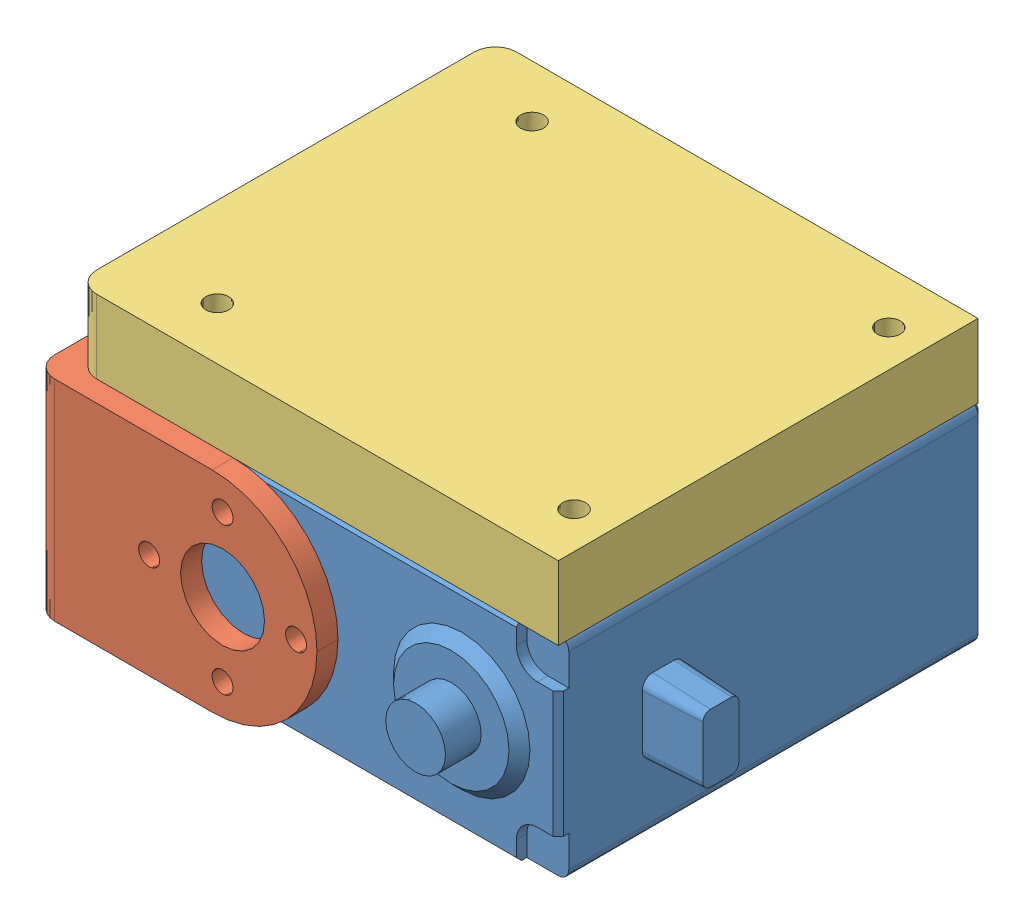
SolidWorks assembly moteur-complet, configuration Défaut. Lengths in mm.
Overall size (56.5 27 48.8).
11 component instances, 5 part files, 26 mates.
Components (placement in the parent):
- moteur-1: moteur [Défaut] at (-9.5825 -1.0731 48.8) size (45.5 20 48.8)
- moteur-support-fixe-1: moteur-support-fixe [Défaut] at (-5.7196 9.1116 15.94) x (1 0 0) z (0 -1 0) size (27.58 44 20)
- moteur_semelle-1: moteur_semelle [Défaut] at (-31.3007 -10.8884 28.8) x (-1 0 0) z (0 0 1) size (46 27 40)
- ecrou-h-1: ecrou-h [6012 HU M3] at (-26.9007 -5.8884 23.8) x (0 0.5 -0.866025) z (0 -0.866025 -0.5) size (5.5 2.4 6.35)
- ecrou-h-2: ecrou-h [6012 HU M3] at (-26.9007 -5.8884 33.8) x (0 -0.5 -0.866025) z (0 -0.866025 0.5) size (5.5 2.4 6.35)
- ecrou-h-3: ecrou-h [6012 HU M3] at (-26.9007 4.1116 33.8) x (0 -0.5 -0.866025) z (0 -0.866025 0.5) size (5.5 2.4 6.35)
- ecrou-h-4: ecrou-h [6012 HU M3] at (-26.9007 4.1116 23.8) x (0 -1 0) z (0 0 1) size (5.5 2.4 6.35)
- vis-chc-1: vis-chc [Vis CHC M3x6] at (-33.3007 -5.8884 33.8) x (0 -0.454411 0.890792) z (0 -0.890792 -0.454411) size (5.5 9 5.5)
- vis-chc-2: vis-chc [Vis CHC M3x6] at (-33.3007 4.1116 33.8) x (0 -0.381849 0.924225) z (0 -0.924225 -0.381849) size (5.5 9 5.5)
- vis-chc-3: vis-chc [Vis CHC M3x6] at (-33.3007 4.1116 23.8) x (0 -0.381849 0.924225) z (0 -0.924225 -0.381849) size (5.5 9 5.5)
- vis-chc-4: vis-chc [Vis CHC M3x6] at (-33.3007 -5.8884 23.8) x (0 -0.381849 0.924225) z (0 -0.924225 -0.381849) size (5.5 9 5.5)
Mates (geometry in assembly coordinates):
- Coaxiale12: concentric aligned: cylinder of moteur-1 through (-22.3007 -0.8884 43.8) axis (0 0 1) radius 0.79; cylinder of moteur-support-fixe-1 through (-22.3007 -0.8884 6.799) axis (0 0 1) radius 1
- Coaxiale13: concentric aligned: cylinder of moteur-1 through (-15.3007 -7.8884 43.8) axis (0 0 1) radius 0.79; cylinder of moteur-support-fixe-1 through (-15.3007 -7.8884 6.799) axis (0 0 1) radius 1
- Coïncidente2: coincident anti-aligned: plane of moteur-1 through (-9.5825 -1.0731 48.8) normal (0 0 1); plane of moteur-support-fixe-1 through (-29.3007 -10.8884 48.8) normal (0 0 -1)
- Coïncidente3: coincident anti-aligned: plane of moteur-support-fixe-1 through (-31.3007 -10.8884 10.8) normal (1 0 0); plane of moteur_semelle-1 through (-31.3007 16.1116 8.8) normal (-1 0 0)
- Coïncidente5: coincident anti-aligned: plane of moteur-1 through (-25.3007 9.1116 8.3) normal (0 1 0); plane of moteur_semelle-1 through (14.6993 9.1116 48.8) normal (0 -1 0)
- Coaxiale15: concentric anti-aligned: cylinder of moteur_semelle-1 through (14.7003 -5.8884 23.8) axis (-1 0 0) radius 1.6; cylinder of ecrou-h-1 through (-29.3007 -5.8884 23.8) axis (1 0 0) radius 1.2295
- Parallèle2: parallel anti-aligned: plane of moteur_semelle-1 through (-29.3007 -8.9195 25.55) normal (0 1 0); plane of ecrou-h-1 through (-29.3007 -8.6384 25.3877) normal (0 -1 0)
- Coïncidente9: coincident anti-aligned: plane of moteur_semelle-1 through (-29.3007 -10.8884 28.8) normal (1 0 0); plane of ecrou-h-1 through (-29.3007 -3.1384 22.2123) normal (-1 0 0)
- Coaxiale16: concentric anti-aligned: cylinder of moteur_semelle-1 through (14.7003 4.1116 33.8) axis (-1 0 0) radius 1.6; cylinder of ecrou-h-3 through (-29.3007 4.1116 33.8) axis (1 0 0) radius 1.2295
- Coaxiale17: concentric anti-aligned: cylinder of moteur_semelle-1 through (14.7003 4.1116 23.8) axis (-1 0 0) radius 1.6; cylinder of ecrou-h-4 through (-29.3007 4.1116 23.8) axis (1 0 0) radius 1.2295
- Coaxiale18: concentric anti-aligned: cylinder of moteur_semelle-1 through (14.7003 -5.8884 33.8) axis (-1 0 0) radius 1.6; cylinder of ecrou-h-2 through (-29.3007 -5.8884 33.8) axis (1 0 0) radius 1.2295
- Parallèle3: parallel anti-aligned: plane of moteur_semelle-1 through (-29.3007 -8.9195 35.55) normal (0 1 0); plane of ecrou-h-2 through (-29.3007 -8.6384 35.3877) normal (0 -1 0)
- Coïncidente11: coincident anti-aligned: plane of moteur_semelle-1 through (-29.3007 -10.8884 28.8) normal (1 0 0); plane of ecrou-h-2 through (-29.3007 -5.8884 30.6246) normal (-1 0 0)
- Parallèle4: parallel anti-aligned: plane of moteur_semelle-1 through (-29.3007 1.0805 25.55) normal (0 1 0); plane of ecrou-h-4 through (-29.3007 1.3616 25.3877) normal (0 -1 0)
- Coïncidente13: coincident anti-aligned: plane of moteur_semelle-1 through (-29.3007 -10.8884 28.8) normal (1 0 0); plane of ecrou-h-4 through (-29.3007 1.3616 22.2123) normal (-1 0 0)
- Parallèle5: parallel anti-aligned: plane of moteur_semelle-1 through (-29.3007 1.0805 35.55) normal (0 1 0); plane of ecrou-h-3 through (-29.3007 1.3616 35.3877) normal (0 -1 0)
- Coïncidente15: coincident anti-aligned: plane of moteur_semelle-1 through (-29.3007 -10.8884 28.8) normal (1 0 0); plane of ecrou-h-3 through (-29.3007 4.1116 30.6246) normal (-1 0 0)
- Coaxiale20: concentric aligned: cylinder of moteur-support-fixe-1 through (-5.7186 -5.8884 33.8) axis (-1 0 0) radius 1.5; cylinder of vis-chc-1 through (-27.3007 -5.8884 33.8) axis (-1 0 0) radius 1.5
- Coaxiale21: concentric aligned: cylinder of moteur-support-fixe-1 through (-5.7186 -5.8884 23.8) axis (-1 0 0) radius 1.5; cylinder of vis-chc-4 through (-27.3007 -5.8884 23.8) axis (-1 0 0) radius 1.5
- Coaxiale22: concentric aligned: cylinder of moteur-support-fixe-1 through (-5.7186 4.1116 23.8) axis (-1 0 0) radius 1.5; cylinder of vis-chc-m2x5-3 through (-27.3007 4.1116 23.8) axis (-1 0 0) radius 1.5
- Coaxiale23: concentric aligned: cylinder of moteur-support-fixe-1 through (-5.7186 4.1116 33.8) axis (-1 0 0) radius 1.5; cylinder of vis-chc-m2x5-2 through (-27.3007 4.1116 33.8) axis (-1 0 0) radius 1.5
- Coïncidente18: coincident anti-aligned: plane of moteur-support-fixe-1 through (-33.3007 -10.8884 48.8) normal (-1 0 0); plane of vis-chc-m2x5-2 through (-33.3007 4.1116 33.8) normal (1 0 0)
- Coïncidente19: coincident anti-aligned: plane of moteur-support-fixe-1 through (-33.3007 -10.8884 48.8) normal (-1 0 0); plane of vis-chc-m2x5-3 through (-33.3007 4.1116 23.8) normal (1 0 0)
- Coïncidente20: coincident anti-aligned: plane of moteur-support-fixe-1 through (-33.3007 -10.8884 48.8) normal (-1 0 0); plane of vis-chc-1 through (-33.3007 -5.8884 33.8) normal (1 0 0)
- Coïncidente21: coincident anti-aligned: plane of moteur-support-fixe-1 through (-33.3007 -10.8884 48.8) normal (-1 0 0); plane of vis-chc-4 through (-33.3007 -5.8884 23.8) normal (1 0 0)
- Coaxiale24: concentric anti-aligned: cylinder of ecrou-h-1 through (-29.3007 -5.8884 23.8) axis (1 0 0) radius 1.2295; cylinder of vis-chc-4 through (-27.3007 -5.8884 23.8) axis (-1 0 0) radius 1.5
